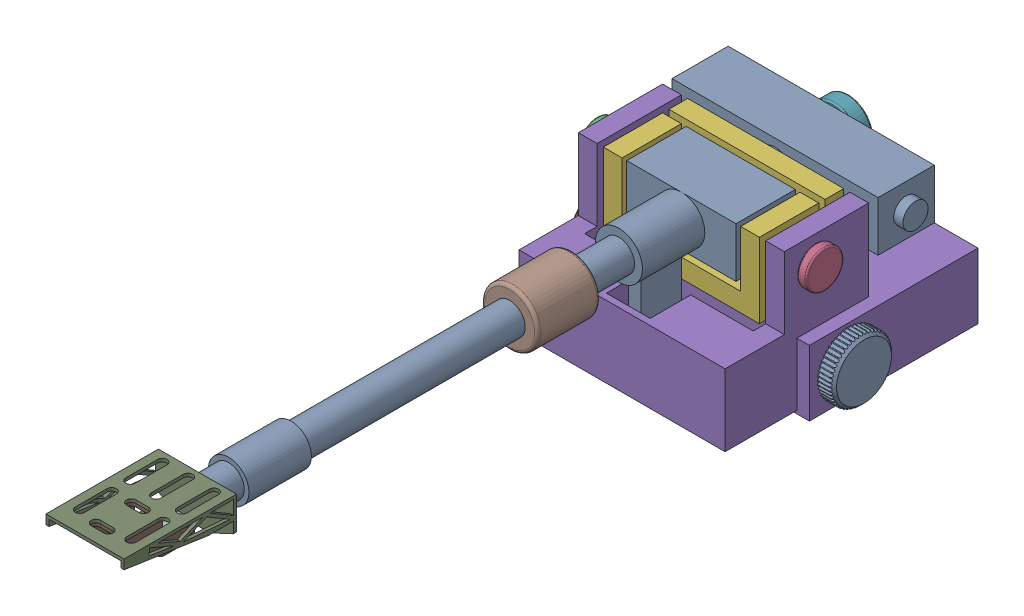
SolidWorks assembly 04_Tone_Arm, configuration Default. Lengths in mm.
Overall size (85 48.5 249).
15 component instances, 11 part files, 0 mates.
Components (placement in the parent):
- Knob.1-1: Knob.1 [Default] at (1104.2898 2.5 -488.1127) x (-1 0 0) z (0 0 -1) size (15 19.96 20)
- Knob.1-2: Knob.1 [Default] at (-0.5 2.5 0) size (15 19.96 20)
- HingPin.2-1: HingPin.2 [Default] at (1103.7898 0 -475.1127) x (-1 0 0) z (0 0 -1) size (17.5 12 12)
- HingPin.2-2: HingPin.2 [Default] at origin size (17.5 12 12)
- Base-1: Base [Default] at origin size (74 47 77)
- Block-1: Block [Default] at (-162 0 0) size (50 24 27)
- Tone_arm-1: Tone_arm [Default] at origin size (72 33.5 244.5)
  - Weight-1: Weight [Default] at (789.4513 0.5 308.8386) x (0 0 -1) z (1 0 0) size (19.5 16 16)
  - Tube_Weight-1: Tube_Weight [Default] at (0 0 -100) size (18 18 20)
  - Bracket-1: Bracket [Default] at origin size (25 14 36)
  - Element-1: Element [Default] at (194.418 86.2072 120.8597) x (1 0 0) z (0 1 0) size (10 27.52 13.64)
    - Needle-1: Needle [Default] at origin size (1.46 6.25 3.18)
    - House-1: House [Default] at (-194.418 123.0355 -85.6815) x (1 0 0) z (0 -1 0) size (10 12 27.52)
    - Connector-1: Connector [Default] at (-194.418 120.8597 -86.2072) x (1 0 0) z (0 -1 0) size (6 5 7.93)
  - Arm-1: Arm [Default] at (-242 0 0) size (72 32 203)
